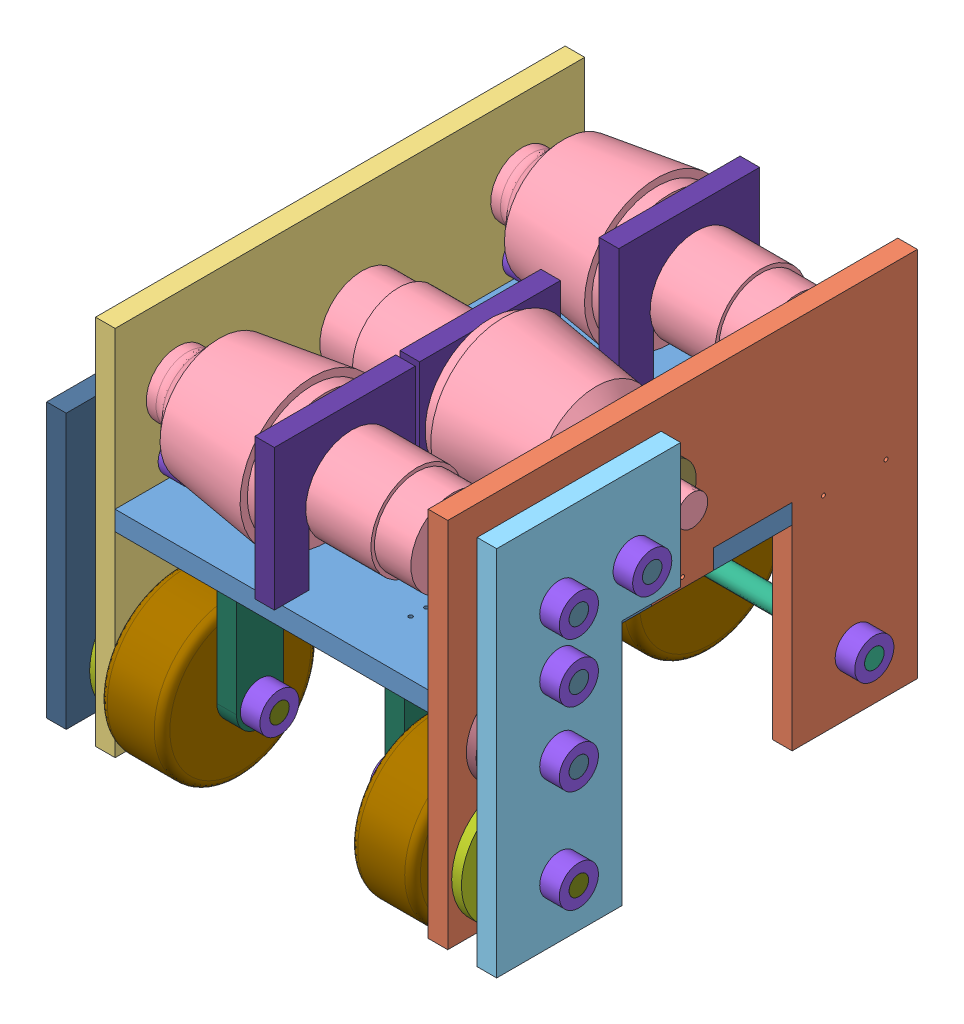
SolidWorks assembly Car_Assembly, configuration Default. Lengths in mm.
Overall size (158.75 139.18 192.65).
80 component instances, 20 part files, 105 mates.
Components (placement in the parent):
- Chassis_Assembly-1: Chassis_Assembly [Default] at (0.9564 18.3844 -4.3666) size (114.3 120.65 152.4)
  - Base_Plate-1: Base_Plate [Default] at (17.453 79.4472 187.1525) size (114.3 6.35 152.4)
  - Side_Plate (1M)-1: Side_Plate (1M) [Default] at (119.053 15.9472 187.1525) x (0 0 -1) z (1 0 0) size (152.4 120.65 6.35)
  - Side_Plate (2M)-1: Side_Plate (2M) [Default] at (11.103 15.9472 187.1525) x (0 0 -1) z (1 0 0) size (152.4 120.65 6.35)
- motor-1: motor [Default] at (107.792 129.5816 50.7059) x (0 -0.283943 -0.958841) z (0 0.958841 -0.283943) size (46.86 107.16 46.86)
- motor-2: motor [Default] at (30.6268 129.5816 114.8409) x (0 -0.869953 0.493135) z (0 0.493135 0.869953) size (46.86 107.16 46.86)
- motor-3: motor [Default] at (107.792 129.5816 162.4659) x (0 0 1) z (0 -1 0) size (46.86 107.16 46.86)
- L_Gear_Cover_Plate-1: L_Gear_Cover_Plate [Default] at (135.8844 34.3316 182.7859) size (6.35 120.65 59.69)
- Back Wheel Assembly-1: Back Wheel Assembly [Default] at (170.5428 21.419 137.1551) x (0 0.966906 -0.255133) z (-1 0 0) size (50.8 50.8 142.88)
  - Back Axel-1: Back Axel [Default] at (52.9609 75.4335 37.8334) size (6.35 6.35 142.88)
  - 72-Gear-1: 72-Gear [Default] at (52.9609 75.4335 158.4834) size (38.1 38.1 9.53)
  - Axel Washer-1: Axel Washer [Default] at (52.9609 75.4335 174.3584) size (12.7 12.7 6.35)
  - Axel Washer-2: Axel Washer [Default] at (52.9609 75.4335 37.8334) size (12.7 12.7 6.35)
  - Wheel-1: Wheel [Default] at (52.9609 75.4335 91.1734) size (50.8 50.8 20.32)
- Straight_Gear_Cover_Plate-1: Straight_Gear_Cover_Plate [Default] at (-3.8156 34.3316 71.0259) size (6.35 88.9 40.64)
- Straight_Gear_Cover_Plate-2: Straight_Gear_Cover_Plate [Default] at (-3.8156 34.3316 182.7859) size (6.35 88.9 40.64)
- 36-Gear-1: 36-Gear [Default] at (12.0594 110.5316 50.7059) x (0 0 1) z (-1 0 0) size (19.05 19.05 7.92)
- 36-Gear for Engine-1: 36-Gear for Engine [Default] at (8.8844 129.5816 50.7059) x (0 0 -1) z (1 0 0) size (19.05 19.05 3.17)
- 54-Gear-1: 54-Gear [Default] at (12.0594 86.7191 50.7059) x (0 0 1) z (-1 0 0) size (28.57 28.57 9.53)
- Train Axel-Washer-1: Train Axel-Washer [Default] at (12.0348 102.2643 53.7119) x (0 0 -1) z (1 0 0) size (13.47 13.47 34.92)
  - Axel Washer-1: Axel Washer [Default] at (3.006 8.2673 6.3746) size (12.7 12.7 6.35)
  - Train Axel-1: Train Axel [Default] at (3.006 8.2673 -22.2004) size (6.35 6.35 34.92)
  - Axel Washer-2: Axel Washer [Default] at (3.006 8.2673 -22.2004) x (0.99803 -0.06274 0) z (0 0 1) size (12.7 12.7 6.35)
- Train Axel-Washer-2: Train Axel-Washer [Default] at (12.0348 78.4518 53.7119) x (0 0 -1) z (1 0 0) size (13.47 13.47 34.92)
  - Axel Washer-1: Axel Washer [Default] at (3.006 8.2673 6.3746) size (12.7 12.7 6.35)
  - Train Axel-1: Train Axel [Default] at (3.006 8.2673 -22.2004) size (6.35 6.35 34.92)
  - Axel Washer-2: Axel Washer [Default] at (3.006 8.2673 -22.2004) x (0.99803 -0.06274 0) z (0 0 1) size (12.7 12.7 6.35)
- Train Axel-Washer-3: Train Axel-Washer [Default] at (12.0348 102.2643 165.4719) x (0 0 -1) z (1 0 0) size (13.47 13.47 34.92)
  - Axel Washer-1: Axel Washer [Default] at (3.006 8.2673 6.3746) size (12.7 12.7 6.35)
  - Train Axel-1: Train Axel [Default] at (3.006 8.2673 -22.2004) size (6.35 6.35 34.92)
  - Axel Washer-2: Axel Washer [Default] at (3.006 8.2673 -22.2004) x (0.99803 -0.06274 0) z (0 0 1) size (12.7 12.7 6.35)
- Train Axel-Washer-4: Train Axel-Washer [Default] at (12.0348 78.4518 165.4719) x (0 0 -1) z (1 0 0) size (13.47 13.47 34.92)
  - Axel Washer-1: Axel Washer [Default] at (3.006 8.2673 6.3746) size (12.7 12.7 6.35)
  - Train Axel-1: Train Axel [Default] at (3.006 8.2673 -22.2004) size (6.35 6.35 34.92)
  - Axel Washer-2: Axel Washer [Default] at (3.006 8.2673 -22.2004) x (0.99803 -0.06274 0) z (0 0 1) size (12.7 12.7 6.35)
- Train Axel-Washer-6: Train Axel-Washer [Default] at (135.8598 129.6778 147.4497) x (0 -0.943484 -0.331418) z (1 0 0) size (13.47 13.47 34.92)
  - Axel Washer-1: Axel Washer [Default] at (3.006 8.2673 6.3746) size (12.7 12.7 6.35)
  - Train Axel-1: Train Axel [Default] at (3.006 8.2673 -22.2004) size (6.35 6.35 34.92)
  - Axel Washer-2: Axel Washer [Default] at (3.006 8.2673 -22.2004) x (0.99803 -0.06274 0) z (0 0 1) size (12.7 12.7 6.35)
- Train Axel-Washer-7: Train Axel-Washer [Default] at (135.8598 102.2643 165.4719) x (0 0 -1) z (1 0 0) size (13.47 13.47 34.92)
  - Axel Washer-1: Axel Washer [Default] at (3.006 8.2673 6.3746) size (12.7 12.7 6.35)
  - Train Axel-1: Train Axel [Default] at (3.006 8.2673 -22.2004) size (6.35 6.35 34.92)
  - Axel Washer-2: Axel Washer [Default] at (3.006 8.2673 -22.2004) x (0.99803 -0.06274 0) z (0 0 1) size (12.7 12.7 6.35)
- Train Axel-Washer-8: Train Axel-Washer [Default] at (135.8598 121.3143 165.4719) x (0 0 -1) z (1 0 0) size (13.47 13.47 34.92)
  - Axel Washer-1: Axel Washer [Default] at (3.006 8.2673 6.3746) size (12.7 12.7 6.35)
  - Train Axel-1: Train Axel [Default] at (3.006 8.2673 -22.2004) size (6.35 6.35 34.92)
  - Axel Washer-2: Axel Washer [Default] at (3.006 8.2673 -22.2004) x (0.99803 -0.06274 0) z (0 0 1) size (12.7 12.7 6.35)
- Train Axel-Washer-9: Train Axel-Washer [Default] at (135.8598 78.4518 165.4719) x (0 0 -1) z (1 0 0) size (13.47 13.47 34.92)
  - Axel Washer-1: Axel Washer [Default] at (3.006 8.2673 6.3746) size (12.7 12.7 6.35)
  - Train Axel-1: Train Axel [Default] at (3.006 8.2673 -22.2004) size (6.35 6.35 34.92)
  - Axel Washer-2: Axel Washer [Default] at (3.006 8.2673 -22.2004) x (0.99803 -0.06274 0) z (0 0 1) size (12.7 12.7 6.35)
- Front Wheel Assembly-1: Front Wheel Assembly [Default] at (96.3289 35.872 169.2289) x (0 0 -1) z (1 0 0) size (50.8 69.85 61.59)
  - 72-Gear-1: 72-Gear [Default] at (6.763 17.5096 30.0306) size (38.1 38.1 9.53)
  - Axel Washer-1: Axel Washer [Default] at (6.763 17.5096 45.9056) size (12.7 12.7 6.35)
  - Front Wheel Support-1: Front Wheel Support [Default] at (6.763 17.5096 -2.9894) size (15.24 52.07 6.35)
  - Front Wheels Axel-1: Front Wheels Axel [Default] at (6.763 17.5096 -9.3394) size (6.35 6.35 61.59)
  - Wheel-1: Wheel [Default] at (6.763 17.5096 3.3606) size (50.8 50.8 20.32)
  - Axel Washer-2: Axel Washer [Default] at (6.763 17.5096 -9.3394) size (12.7 12.7 6.35)
- Front Wheel Assembly-2: Front Wheel Assembly [Default] at (42.09 35.872 155.7029) x (0 0 1) z (-1 0 0) size (50.8 69.85 61.59)
  - 72-Gear-1: 72-Gear [Default] at (6.763 17.5096 30.0306) size (38.1 38.1 9.53)
  - Axel Washer-1: Axel Washer [Default] at (6.763 17.5096 45.9056) size (12.7 12.7 6.35)
  - Front Wheel Support-1: Front Wheel Support [Default] at (6.763 17.5096 -2.9894) size (15.24 52.07 6.35)
  - Front Wheels Axel-1: Front Wheels Axel [Default] at (6.763 17.5096 -9.3394) size (6.35 6.35 61.59)
  - Wheel-1: Wheel [Default] at (6.763 17.5096 3.3606) size (50.8 50.8 20.32)
  - Axel Washer-2: Axel Washer [Default] at (6.763 17.5096 -9.3394) size (12.7 12.7 6.35)
- 36-Gear for Engine-2: 36-Gear for Engine [Default] at (12.0594 129.5816 162.4659) x (0 0 1) z (-1 0 0) size (19.05 19.05 3.17)
- 36-Gear-2: 36-Gear [Default] at (12.0594 110.5316 162.4659) x (0 0 1) z (-1 0 0) size (19.05 19.05 7.92)
- 54-Gear-2: 54-Gear [Default] at (12.0594 86.7191 162.4659) x (0 0 1) z (-1 0 0) size (28.57 28.57 9.53)
- 36-Gear for Engine-3: 36-Gear for Engine [Default] at (126.3594 129.5816 114.8409) x (0 -0.999929 0.011916) z (1 0 0) size (19.05 19.05 3.17)
- 54-Gear-3: 54-Gear [Default] at (126.3594 129.5816 138.6534) x (0 0.866025 0.5) z (1 0 0) size (28.57 28.57 9.53)
- 36-Gear-3: 36-Gear [Default] at (126.3594 129.5816 162.4659) x (0 0 1) z (1 0 0) size (19.05 19.05 7.92)
- 54-Gear-4: 54-Gear [Default] at (126.3594 86.7191 162.4659) x (0 -0.976943 0.213502) z (1 0 0) size (28.57 28.57 9.53)
- 36-Gear-4: 36-Gear [Default] at (126.3594 110.5316 162.4659) x (0 0 1) z (1 0 0) size (19.05 19.05 7.92)
- Motor_Support-1: Motor_Support [Default] at (65.7804 104.1816 137.7009) x (0 0 -1) z (1 0 0) size (45.72 45.72 6.35)
- Motor_Support-2: Motor_Support [Default] at (66.2884 104.1816 73.5659) x (0 0 -1) z (1 0 0) size (45.72 45.72 6.35)
- Motor_Support-3: Motor_Support [Default] at (72.6384 104.1816 139.6059) x (0 0 1) z (-1 0 0) size (45.72 45.72 6.35)
- Trailer_Hitch-1: Trailer_Hitch [Default] at (-22.7854 42.9374 106.4315) x (-0.99987 -0.014413 -0.007232) z (0.006979 0.017505 -0.999822) size (19.78 26.55 50.7)
  - Trailer_Arm_H-1: Trailer_Arm_H [Default] at (-102.7636 52.344 61.8357) x (0.99987 0.014537 -0.006979) z (0.014413 -0.999743 -0.017505) size (19.05 25.4 6.35)
  - Trailer_Arm_V-1: Trailer_Arm_V [Default] at (-102.2597 26.619 80.4377) x (0.99987 0.014537 -0.006979) z (0.007232 -0.017403 0.999822) size (19.05 25.4 6.35)
  - Trailer_Hook-1: Trailer_Hook [Default] at (-102.3512 32.9674 80.5488) x (0.99987 0.014537 -0.006979) z (0.014413 -0.999743 -0.017505) size (19.05 31.75 6.35)
Mates (geometry in assembly coordinates):
- Concentric1: concentric aligned: cylinder of Chassis_Assembly-1/Side_Plate (1M)-1 through (126.3594 129.5816 114.8409) axis (-1 0 0) radius 4.7371; cylinder of motor-2 through (137.7894 129.5816 114.8409) axis (-1 0 0) radius 4.9911
- Coincident1: coincident anti-aligned: plane of Chassis_Assembly-1/Side_Plate (1M)-1 through (120.0094 34.3316 182.7859) normal (-1 0 0); circle of motor-2
- Concentric2: concentric anti-aligned: cylinder of Chassis_Assembly-1/Side_Plate (2M)-1 through (18.4094 129.5816 50.7059) axis (-1 0 0) radius 4.7371; cylinder of motor-1 through (0.6294 129.5816 50.7059) axis (1 0 0) radius 4.9911
- Coincident2: coincident anti-aligned: plane of Chassis_Assembly-1/Side_Plate (2M)-1 through (18.4094 34.3316 182.7859) normal (1 0 0); plane of motor-1 through (18.4094 129.5816 50.7059) normal (-1 0 0)
- Concentric3: concentric anti-aligned: cylinder of Chassis_Assembly-1/Side_Plate (2M)-1 through (18.4094 129.5816 162.4659) axis (-1 0 0) radius 4.7371; cylinder of motor-3 through (0.6294 129.5816 162.4659) axis (1 0 0) radius 4.9911
- Coincident3: coincident anti-aligned: plane of Chassis_Assembly-1/Side_Plate (2M)-1 through (18.4094 34.3316 182.7859) normal (1 0 0); plane of motor-3 through (18.4094 129.5816 162.4659) normal (-1 0 0)
- Concentric4: concentric aligned: cylinder of Chassis_Assembly-1/Side_Plate (1M)-1 through (126.3594 129.5816 114.8409) axis (-1 0 0) radius 4.7371; cylinder of motor-2 through (137.7894 129.5816 114.8409) axis (-1 0 0) radius 4.9911
- Concentric5: concentric: cylinder of ? through (124.1016 50.6336 58.4232) axis (-1 0 0) radius 3.175; cylinder of Chassis_Assembly-1/Side_Plate (1M)-1 through (111.3488 50.6336 58.4232) axis (-1 0 0) radius 3.175
- Concentric6: concentric aligned: cylinder of ? through (124.1016 50.6336 58.4232) axis (-1 0 0) radius 3.175; cylinder of Chassis_Assembly-1/Side_Plate (2M)-1 through (3.3988 50.6336 58.4232) axis (-1 0 0) radius 3.175
- Coincident4: coincident aligned: plane of Chassis_Assembly-1/Side_Plate (1M)-1 through (126.3594 154.9816 182.7859) normal (0 1 0); plane of L_Gear_Cover_Plate-1 through (142.2344 154.9816 182.7859) normal (0 1 0)
- Coincident5: coincident aligned: plane of Chassis_Assembly-1/Side_Plate (1M)-1 through (126.3594 104.1816 182.7859) normal (0 0 1); plane of L_Gear_Cover_Plate-1 through (142.2344 34.3316 182.7859) normal (0 0 1)
- Concentric7: concentric anti-aligned: cylinder of Chassis_Assembly-1/Side_Plate (1M)-1 through (126.3594 53.3816 50.7059) axis (-1 0 0) radius 3.175; cylinder of ? through (-10.1656 53.3816 50.7059) axis (1 0 0) radius 3.175
- Coincident9: coincident anti-aligned: plane of Chassis_Assembly-1/Side_Plate (1M)-1 through (126.3594 34.3316 182.7859) normal (1 0 0); plane of Back Wheel Assembly-1/Axel Washer-2 through (126.3594 53.3816 50.7059) normal (-1 0 0)
- Concentric8: concentric aligned: cylinder of ? through (-10.1656 53.3816 50.7059) axis (1 0 0) radius 3.175; cylinder of Straight_Gear_Cover_Plate-1 through (-3.8156 53.3816 50.7059) axis (1 0 0) radius 3.175
- Coincident10: coincident anti-aligned: plane of Back Wheel Assembly-1/Axel Washer-1 through (-3.8156 53.3816 50.7059) normal (1 0 0); plane of Straight_Gear_Cover_Plate-1 through (-3.8156 34.3316 71.0259) normal (-1 0 0)
- Coincident11: coincident anti-aligned: plane of Chassis_Assembly-1/Side_Plate (2M)-1 through (12.0594 34.3316 182.7859) normal (-1 0 0); plane of 36-Gear for Engine-1 through (12.0594 129.5816 50.7059) normal (1 0 0)
- Concentric10: concentric aligned: cylinder of motor-1 through (0.6294 129.5816 50.7059) axis (1 0 0) radius 4.9911; cylinder of 36-Gear for Engine-1 through (8.8336 129.5816 50.7059) axis (1 0 0) radius 4.9784
- Coincident12: coincident anti-aligned: plane of Chassis_Assembly-1/Side_Plate (2M)-1 through (12.0594 34.3316 182.7859) normal (-1 0 0); plane of 36-Gear-1 through (12.0594 110.5316 50.7059) normal (1 0 0)
- Concentric11: concentric anti-aligned: cylinder of Straight_Gear_Cover_Plate-1 through (-18.8262 107.7836 58.4232) axis (1 0 0) radius 3.175; cylinder of ? through (6.3229 107.7836 58.4232) axis (-1 0 0) radius 3.175
- Concentric12: concentric anti-aligned: cylinder of Straight_Gear_Cover_Plate-1 through (-3.8156 110.5316 50.7059) axis (1 0 0) radius 3.175; cylinder of Chassis_Assembly-1/Side_Plate (2M)-1 through (18.4094 110.5316 50.7059) axis (-1 0 0) radius 3.175
- Concentric13: concentric anti-aligned: cylinder of ? through (5.7234 83.9711 58.4232) axis (-1 0 0) radius 3.175; cylinder of Straight_Gear_Cover_Plate-1 through (-18.8262 83.9711 58.4232) axis (1 0 0) radius 3.175
- Concentric14: concentric aligned: cylinder of ? through (5.7234 83.9711 58.4232) axis (-1 0 0) radius 3.175; cylinder of Chassis_Assembly-1/Side_Plate (2M)-1 through (3.3988 83.9711 58.4232) axis (-1 0 0) radius 3.175
- Concentric15: concentric aligned: cylinder of 36-Gear-1 through (-2.9004 107.7836 58.4232) axis (-1 0 0) radius 3.175; cylinder of ? through (6.3229 107.7836 58.4232) axis (-1 0 0) radius 3.175
- Coincident13: coincident anti-aligned: plane of Chassis_Assembly-1/Side_Plate (2M)-1 through (12.0594 34.3316 182.7859) normal (-1 0 0); plane of 54-Gear-1 through (12.0594 86.7191 50.7059) normal (1 0 0)
- Concentric16: concentric anti-aligned: cylinder of ? through (5.7234 83.9711 58.4232) axis (-1 0 0) radius 3.175; cylinder of 54-Gear-1 through (-14.3812 83.9711 58.4232) axis (1 0 0) radius 3.175
- Concentric19: concentric aligned: cylinder of Train Axel-Washer-1/Train Axel-1 through (24.7594 110.5316 50.7059) axis (-1 0 0) radius 3.175; cylinder of Chassis_Assembly-1/Side_Plate (2M)-1 through (18.4094 110.5316 50.7059) axis (-1 0 0) radius 3.175
- Concentric20: concentric anti-aligned: cylinder of Train Axel-Washer-1/Train Axel-1 through (24.7594 110.5316 50.7059) axis (-1 0 0) radius 3.175; cylinder of Straight_Gear_Cover_Plate-1 through (-3.8156 110.5316 50.7059) axis (1 0 0) radius 3.175
- Coincident14: coincident anti-aligned: plane of Train Axel-Washer-1/Axel Washer-1 through (18.4094 110.5316 50.7059) normal (-1 0 0); plane of Chassis_Assembly-1/Side_Plate (2M)-1 through (18.4094 34.3316 182.7859) normal (1 0 0)
- Concentric21: concentric aligned: cylinder of Train Axel-Washer-2/Train Axel-1 through (24.7594 86.7191 50.7059) axis (-1 0 0) radius 3.175; cylinder of Chassis_Assembly-1/Side_Plate (2M)-1 through (18.4094 86.7191 50.7059) axis (-1 0 0) radius 3.175
- Concentric22: concentric anti-aligned: cylinder of Train Axel-Washer-2/Train Axel-1 through (24.7594 86.7191 50.7059) axis (-1 0 0) radius 3.175; cylinder of Straight_Gear_Cover_Plate-1 through (-3.8156 86.7191 50.7059) axis (1 0 0) radius 3.175
- Coincident15: coincident anti-aligned: plane of Train Axel-Washer-2/Axel Washer-1 through (18.4094 86.7191 50.7059) normal (-1 0 0); plane of Chassis_Assembly-1/Side_Plate (2M)-1 through (18.4094 34.3316 182.7859) normal (1 0 0)
- Coincident18: coincident anti-aligned: plane of Chassis_Assembly-1/Side_Plate (2M)-1 through (12.0594 34.3316 182.7859) normal (-1 0 0); plane of 36-Gear-1 through (12.0594 110.5316 50.7059) normal (1 0 0)
- Coincident19: coincident anti-aligned: plane of Chassis_Assembly-1/Side_Plate (2M)-1 through (12.0594 34.3316 182.7859) normal (-1 0 0); plane of 54-Gear-1 through (12.0594 86.7191 50.7059) normal (1 0 0)
- Concentric23: concentric anti-aligned: cylinder of 54-Gear-1 through (0.6294 86.7191 50.7059) axis (1 0 0) radius 3.175; cylinder of Train Axel-Washer-2/Train Axel-1 through (24.7594 86.7191 50.7059) axis (-1 0 0) radius 3.175
- Concentric24: concentric aligned: cylinder of 36-Gear-1 through (12.1102 110.5316 50.7059) axis (-1 0 0) radius 3.175; cylinder of Train Axel-Washer-1/Train Axel-1 through (24.7594 110.5316 50.7059) axis (-1 0 0) radius 3.175
- Coincident20: coincident anti-aligned: plane of Chassis_Assembly-1/Side_Plate (2M)-1 through (18.4094 34.3316 182.7859) normal (1 0 0); plane of Train Axel-Washer-3/Axel Washer-1 through (18.4094 110.5316 162.4659) normal (-1 0 0)
- Concentric25: concentric aligned: cylinder of Chassis_Assembly-1/Side_Plate (2M)-1 through (18.4094 110.5316 162.4659) axis (-1 0 0) radius 3.175; cylinder of Train Axel-Washer-3/Train Axel-1 through (24.7594 110.5316 162.4659) axis (-1 0 0) radius 3.175
- Coincident21: coincident anti-aligned: plane of Chassis_Assembly-1/Side_Plate (2M)-1 through (18.4094 34.3316 182.7859) normal (1 0 0); plane of Train Axel-Washer-4/Axel Washer-1 through (18.4094 86.7191 162.4659) normal (-1 0 0)
- Concentric26: concentric aligned: cylinder of Chassis_Assembly-1/Side_Plate (2M)-1 through (18.4094 86.7191 162.4659) axis (-1 0 0) radius 3.175; cylinder of Train Axel-Washer-4/Train Axel-1 through (24.7594 86.7191 162.4659) axis (-1 0 0) radius 3.175
- Coincident22: coincident anti-aligned: plane of Chassis_Assembly-1/Side_Plate (2M)-1 through (3.3988 31.5836 190.5032) normal (1 0 0); plane of ? through (3.3988 50.6336 170.1832) normal (-1 0 0)
- Concentric27: concentric aligned: cylinder of Chassis_Assembly-1/Side_Plate (2M)-1 through (3.3988 50.6336 170.1832) axis (-1 0 0) radius 3.175; cylinder of ? through (9.7488 50.6336 170.1832) axis (-1 0 0) radius 3.175
- Coincident23: coincident anti-aligned: plane of Straight_Gear_Cover_Plate-2 through (-3.8156 34.3316 182.7859) normal (-1 0 0); plane of Train Axel-Washer-3/Axel Washer-2 through (-3.8156 110.5316 162.4659) normal (1 0 0)
- Coincident24: coincident anti-aligned: plane of Straight_Gear_Cover_Plate-2 through (-3.8156 34.3316 182.7859) normal (-1 0 0); plane of Train Axel-Washer-4/Axel Washer-2 through (-3.8156 86.7191 162.4659) normal (1 0 0)
- Concentric29: concentric anti-aligned: cylinder of Straight_Gear_Cover_Plate-2 through (-3.8156 86.7191 162.4659) axis (1 0 0) radius 3.175; cylinder of Train Axel-Washer-4/Train Axel-1 through (24.7594 86.7191 162.4659) axis (-1 0 0) radius 3.175
- Concentric30: concentric anti-aligned: cylinder of Straight_Gear_Cover_Plate-2 through (-3.8156 110.5316 162.4659) axis (1 0 0) radius 3.175; cylinder of Train Axel-Washer-3/Train Axel-1 through (24.7594 110.5316 162.4659) axis (-1 0 0) radius 3.175
- Coincident25: coincident anti-aligned: plane of Chassis_Assembly-1/Side_Plate (1M)-1 through (120.0094 34.3316 182.7859) normal (-1 0 0); plane of Train Axel-Washer-6/Axel Washer-2 through (120.0094 129.5816 138.6534) normal (1 0 0)
- Coincident26: coincident anti-aligned: plane of Chassis_Assembly-1/Side_Plate (1M)-1 through (120.0094 34.3316 182.7859) normal (-1 0 0); plane of Train Axel-Washer-8/Axel Washer-2 through (120.0094 129.5816 162.4659) normal (1 0 0)
- Coincident27: coincident anti-aligned: plane of Chassis_Assembly-1/Side_Plate (1M)-1 through (120.0094 34.3316 182.7859) normal (-1 0 0); plane of Train Axel-Washer-7/Axel Washer-2 through (120.0094 110.5316 162.4659) normal (1 0 0)
- Concentric31: concentric aligned: cylinder of Chassis_Assembly-1/Side_Plate (1M)-1 through (126.3594 129.5816 138.6534) axis (-1 0 0) radius 3.175; cylinder of Train Axel-Washer-6/Train Axel-1 through (148.5844 129.5816 138.6534) axis (-1 0 0) radius 3.175
- Concentric32: concentric aligned: cylinder of Chassis_Assembly-1/Side_Plate (1M)-1 through (126.3594 129.5816 162.4659) axis (-1 0 0) radius 3.175; cylinder of Train Axel-Washer-8/Train Axel-1 through (148.5844 129.5816 162.4659) axis (-1 0 0) radius 3.175
- Concentric33: concentric aligned: cylinder of Chassis_Assembly-1/Side_Plate (1M)-1 through (126.3594 110.5316 162.4659) axis (-1 0 0) radius 3.175; cylinder of Train Axel-Washer-7/Train Axel-1 through (148.5844 110.5316 162.4659) axis (-1 0 0) radius 3.175
- Coincident28: coincident anti-aligned: plane of Chassis_Assembly-1/Side_Plate (1M)-1 through (120.0094 34.3316 182.7859) normal (-1 0 0); plane of Train Axel-Washer-9/Axel Washer-2 through (120.0094 86.7191 162.4659) normal (1 0 0)
- Concentric34: concentric aligned: cylinder of Chassis_Assembly-1/Side_Plate (1M)-1 through (126.3594 86.7191 162.4659) axis (-1 0 0) radius 3.175; cylinder of Train Axel-Washer-9/Train Axel-1 through (148.5844 86.7191 162.4659) axis (-1 0 0) radius 3.175
- Concentric35: concentric anti-aligned: cylinder of L_Gear_Cover_Plate-1 through (135.8844 129.5816 162.4659) axis (1 0 0) radius 3.175; cylinder of Train Axel-Washer-8/Train Axel-1 through (148.5844 129.5816 162.4659) axis (-1 0 0) radius 3.175
- Concentric36: concentric anti-aligned: cylinder of L_Gear_Cover_Plate-1 through (135.8844 110.5316 162.4659) axis (1 0 0) radius 3.175; cylinder of Train Axel-Washer-7/Train Axel-1 through (148.5844 110.5316 162.4659) axis (-1 0 0) radius 3.175
- Concentric37: concentric anti-aligned: cylinder of L_Gear_Cover_Plate-1 through (135.8844 129.5816 138.6534) axis (1 0 0) radius 3.175; cylinder of Train Axel-Washer-6/Train Axel-1 through (148.5844 129.5816 138.6534) axis (-1 0 0) radius 3.175
- Coincident31: coincident anti-aligned: plane of L_Gear_Cover_Plate-1 through (142.2344 34.3316 182.7859) normal (1 0 0); plane of Train Axel-Washer-8/Axel Washer-1 through (142.2344 129.5816 162.4659) normal (-1 0 0)
- Concentric38: concentric aligned: cylinder of Chassis_Assembly-1/Side_Plate (1M)-1 through (126.3594 53.3816 162.4659) axis (-1 0 0) radius 3.175; cylinder of Front Wheel Assembly-1/Front Wheels Axel-1 through (148.5844 53.3816 162.4659) axis (-1 0 0) radius 3.175
- Coincident32: coincident anti-aligned: plane of Chassis_Assembly-1/Base_Plate-1 through (18.4094 97.8316 182.7859) normal (0 -1 0); plane of Front Wheel Assembly-1/Front Wheel Support-1 through (99.6894 97.8316 170.0859) normal (0 1 0)
- Coincident33: coincident anti-aligned: plane of Chassis_Assembly-1/Side_Plate (1M)-1 through (120.0094 34.3316 182.7859) normal (-1 0 0); plane of Front Wheel Assembly-1/Wheel-1 through (120.0094 53.3816 162.4659) normal (1 0 0)
- Concentric39: concentric aligned: cylinder of Straight_Gear_Cover_Plate-2 through (-3.8156 53.3816 162.4659) axis (1 0 0) radius 3.175; cylinder of Front Wheel Assembly-2/Front Wheels Axel-1 through (-10.1656 53.3816 162.4659) axis (1 0 0) radius 3.175
- Coincident34: coincident anti-aligned: plane of Chassis_Assembly-1/Base_Plate-1 through (18.4094 97.8316 182.7859) normal (0 -1 0); plane of Front Wheel Assembly-2/Front Wheel Support-1 through (38.7294 97.8316 154.8459) normal (0 1 0)
- Coincident35: coincident anti-aligned: plane of Chassis_Assembly-1/Side_Plate (2M)-1 through (18.4094 34.3316 182.7859) normal (1 0 0); plane of Front Wheel Assembly-2/Wheel-1 through (18.4094 53.3816 162.4659) normal (-1 0 0)
- Concentric40: concentric anti-aligned: cylinder of motor-3 through (0.6294 129.5816 162.4659) axis (1 0 0) radius 4.9911; cylinder of 36-Gear for Engine-2 through (12.1102 129.5816 162.4659) axis (-1 0 0) radius 4.9784
- Coincident36: coincident anti-aligned: plane of Chassis_Assembly-1/Side_Plate (2M)-1 through (12.0594 34.3316 182.7859) normal (-1 0 0); plane of 36-Gear for Engine-2 through (12.0594 129.5816 162.4659) normal (1 0 0)
- Concentric41: concentric aligned: cylinder of Train Axel-Washer-3/Train Axel-1 through (24.7594 110.5316 162.4659) axis (-1 0 0) radius 3.175; cylinder of 36-Gear-2 through (12.1102 110.5316 162.4659) axis (-1 0 0) radius 3.175
- Coincident37: coincident anti-aligned: plane of Chassis_Assembly-1/Side_Plate (2M)-1 through (12.0594 34.3316 182.7859) normal (-1 0 0); plane of 36-Gear-2 through (12.0594 110.5316 162.4659) normal (1 0 0)
- Concentric42: concentric anti-aligned: cylinder of Train Axel-Washer-4/Train Axel-1 through (24.7594 86.7191 162.4659) axis (-1 0 0) radius 3.175; cylinder of 54-Gear-2 through (0.6294 86.7191 162.4659) axis (1 0 0) radius 3.175
- Coincident38: coincident anti-aligned: plane of Chassis_Assembly-1/Side_Plate (2M)-1 through (12.0594 34.3316 182.7859) normal (-1 0 0); plane of 54-Gear-2 through (12.0594 86.7191 162.4659) normal (1 0 0)
- Concentric43: concentric anti-aligned: cylinder of motor-2 through (137.7894 129.5816 114.8409) axis (-1 0 0) radius 4.9911; cylinder of 36-Gear for Engine-3 through (126.3086 129.5816 114.8409) axis (1 0 0) radius 4.9784
- Coincident39: coincident anti-aligned: plane of Chassis_Assembly-1/Side_Plate (1M)-1 through (126.3594 34.3316 182.7859) normal (1 0 0); plane of 36-Gear for Engine-3 through (126.3594 129.5816 114.8409) normal (-1 0 0)
- Concentric44: concentric aligned: cylinder of Train Axel-Washer-6/Train Axel-1 through (148.5844 129.5816 138.6534) axis (-1 0 0) radius 3.175; cylinder of 54-Gear-3 through (137.7894 129.5816 138.6534) axis (-1 0 0) radius 3.175
- Coincident40: coincident anti-aligned: plane of Chassis_Assembly-1/Side_Plate (1M)-1 through (126.3594 34.3316 182.7859) normal (1 0 0); plane of 54-Gear-3 through (126.3594 129.5816 138.6534) normal (-1 0 0)
- Concentric45: concentric anti-aligned: cylinder of Train Axel-Washer-8/Train Axel-1 through (148.5844 129.5816 162.4659) axis (-1 0 0) radius 3.175; cylinder of 36-Gear-3 through (126.3086 129.5816 162.4659) axis (1 0 0) radius 3.175
- Coincident41: coincident anti-aligned: plane of Chassis_Assembly-1/Side_Plate (1M)-1 through (126.3594 34.3316 182.7859) normal (1 0 0); plane of 36-Gear-3 through (126.3594 129.5816 162.4659) normal (-1 0 0)
- Concentric46: concentric aligned: cylinder of Train Axel-Washer-9/Train Axel-1 through (148.5844 86.7191 162.4659) axis (-1 0 0) radius 3.175; cylinder of 54-Gear-4 through (137.7894 86.7191 162.4659) axis (-1 0 0) radius 3.175
- Coincident42: coincident anti-aligned: plane of Chassis_Assembly-1/Side_Plate (1M)-1 through (126.3594 34.3316 182.7859) normal (1 0 0); plane of 54-Gear-4 through (126.3594 86.7191 162.4659) normal (-1 0 0)
- Concentric47: concentric anti-aligned: cylinder of Train Axel-Washer-7/Train Axel-1 through (148.5844 110.5316 162.4659) axis (-1 0 0) radius 3.175; cylinder of 36-Gear-4 through (126.3086 110.5316 162.4659) axis (1 0 0) radius 3.175
- Coincident44: coincident anti-aligned: plane of Chassis_Assembly-1/Side_Plate (1M)-1 through (126.3594 34.3316 182.7859) normal (1 0 0); plane of 36-Gear-4 through (126.3594 110.5316 162.4659) normal (-1 0 0)
- Coincident51: coincident anti-aligned: plane of Chassis_Assembly-1/Base_Plate-1 through (3.3988 95.0836 190.5032) normal (0 -1 0); plane of ? through (46.2869 95.0836 25.4032) normal (0 1 0)
- Distance4: distance = 50.8 mm: moEndPointRef_w of ?; line of Chassis_Assembly-1/Side_Plate (1M)-1 through (104.9988 31.5836 38.1032) axis (0 1 0)
- Distance6: distance = 12.7 mm: line of ? through (46.2869 95.0836 25.4032) axis (1 0 0); line of Chassis_Assembly-1/Base_Plate-1 through (104.9988 95.0836 38.1032) axis (-1 0 0)
- Concentric50: concentric anti-aligned: cylinder of motor-1 through (66.2884 129.5816 50.7059) axis (1 0 0) radius 11.6205; cylinder of Motor_Support-2 through (72.6384 129.5816 50.7059) axis (-1 0 0) radius 11.6205
- Coincident70: coincident anti-aligned: plane of motor-1 through (66.2884 129.5816 50.7059) normal (1 0 0); plane of Motor_Support-2 through (66.2884 129.5816 50.7059) normal (-1 0 0)
- Coincident73: coincident anti-aligned: plane of Chassis_Assembly-1/Base_Plate-1 through (18.4094 97.8316 182.7859) normal (0 -1 0); plane of Trailer_Hitch-1/Trailer_Arm_H-1 through (79.6354 97.8316 46.2609) normal (0 1 0)
- Concentric52: concentric aligned: cylinder of motor-3 through (66.2884 129.5816 162.4659) axis (1 0 0) radius 11.6205; cylinder of Motor_Support-3 through (66.2884 129.5816 162.4659) axis (1 0 0) radius 11.6205
- Coincident75: coincident anti-aligned: plane of Chassis_Assembly-1/Base_Plate-1 through (18.4094 104.1816 182.7859) normal (0 1 0); plane of Motor_Support-3 through (66.2884 104.1816 174.0864) normal (0 -1 0)
- Coincident76: coincident anti-aligned: plane of motor-3 through (66.2884 129.5816 162.4659) normal (1 0 0); plane of Motor_Support-3 through (66.2884 129.5816 162.4659) normal (-1 0 0)
- Concentric53: concentric aligned: cylinder of motor-2 through (72.1304 129.5816 114.8409) axis (-1 0 0) radius 11.6205; cylinder of Motor_Support-1 through (72.1304 129.5816 114.8409) axis (-1 0 0) radius 11.6205
- Coincident77: coincident anti-aligned: plane of Chassis_Assembly-1/Base_Plate-1 through (18.4094 104.1816 182.7859) normal (0 1 0); plane of Motor_Support-1 through (72.1304 104.1816 103.2204) normal (0 -1 0)
- Coincident78: coincident anti-aligned: plane of motor-2 through (72.1304 129.5816 114.8409) normal (-1 0 0); plane of Motor_Support-1 through (72.1304 129.5816 114.8409) normal (1 0 0)
- Coincident79: coincident anti-aligned: plane of Chassis_Assembly-1/Base_Plate-1 through (18.4094 104.1816 182.7859) normal (0 1 0); plane of Motor_Support-2 through (72.6384 104.1816 39.0854) normal (0 -1 0)
- GearMate1: gear = 19.05 : 19.05 mm: cylinder of 36-Gear for Engine-1 through (12.0594 129.5816 50.7059) axis (-1 0 0) radius 9.525; cylinder of 36-Gear-1 through (8.8844 110.5316 50.7059) axis (1 0 0) radius 9.525
- GearMate2: gear = 28.575 : 19.05 mm: cylinder of 36-Gear-1 through (8.8844 110.5316 50.7059) axis (1 0 0) radius 9.525; cylinder of 54-Gear-1 through (8.8844 86.7191 50.7059) axis (1 0 0) radius 14.2875
- GearMate3: gear = 28.575 : 38.1 mm: cylinder of Back Wheel Assembly-1/72-Gear-1 through (8.8844 53.3816 50.7059) axis (1 0 0) radius 19.05; cylinder of 54-Gear-1 through (8.8844 86.7191 50.7059) axis (1 0 0) radius 14.2875
- GearMate4: gear = 19.05 : 19.05 mm: cylinder of 36-Gear for Engine-2 through (8.8844 129.5816 162.4659) axis (1 0 0) radius 9.525; cylinder of 36-Gear-2 through (8.8844 110.5316 162.4659) axis (1 0 0) radius 9.525
- GearMate5: gear = 28.575 : 19.05 mm: cylinder of 36-Gear-2 through (8.8844 110.5316 162.4659) axis (1 0 0) radius 9.525; cylinder of 54-Gear-2 through (8.8844 86.7191 162.4659) axis (1 0 0) radius 14.2875
- GearMate6: gear = 38.1 : 28.575 mm: cylinder of 54-Gear-2 through (8.8844 86.7191 162.4659) axis (1 0 0) radius 14.2875; cylinder of Front Wheel Assembly-2/72-Gear-1 through (8.8844 53.3816 162.4659) axis (1 0 0) radius 19.05
- GearMate7: gear = 28.575 : 19.05 mm: cylinder of 36-Gear for Engine-3 through (129.5344 129.5816 114.8409) axis (-1 0 0) radius 9.525; cylinder of 54-Gear-3 through (129.5344 129.5816 138.6534) axis (-1 0 0) radius 14.2875
- GearMate8: gear = 19.05 : 28.575 mm: cylinder of 54-Gear-3 through (129.5344 129.5816 138.6534) axis (-1 0 0) radius 14.2875; cylinder of 36-Gear-3 through (129.5344 129.5816 162.4659) axis (-1 0 0) radius 9.525
- GearMate9: gear = 19.05 : 19.05 mm: cylinder of 36-Gear-3 through (129.5344 129.5816 162.4659) axis (-1 0 0) radius 9.525; cylinder of 36-Gear-4 through (129.5344 110.5316 162.4659) axis (-1 0 0) radius 9.525
- GearMate10: gear = 28.575 : 19.05 mm: cylinder of 36-Gear-4 through (129.5344 110.5316 162.4659) axis (-1 0 0) radius 9.525; cylinder of 54-Gear-4 through (129.5344 86.7191 162.4659) axis (-1 0 0) radius 14.2875
- GearMate11: gear = 38.1 : 28.575 mm: cylinder of 54-Gear-4 through (129.5344 86.7191 162.4659) axis (-1 0 0) radius 14.2875; cylinder of Front Wheel Assembly-1/72-Gear-1 through (129.5344 53.3816 162.4659) axis (-1 0 0) radius 19.05
- Distance7: distance = 15.875 mm anti-aligned: plane of Trailer_Hitch-1/Trailer_Arm_H-1 through (79.6354 91.4816 46.2609) normal (0 0 1); plane of Chassis_Assembly-1/Base_Plate-1 through (18.4094 104.1816 30.3859) normal (0 0 -1)
- Distance8: distance = 50.8 mm: moEndPointRef_w of Trailer_Hitch-1/Trailer_Arm_H-1; line of Chassis_Assembly-1/Base_Plate-1 through (120.0094 104.1816 30.3859) axis (0 -1 0)
